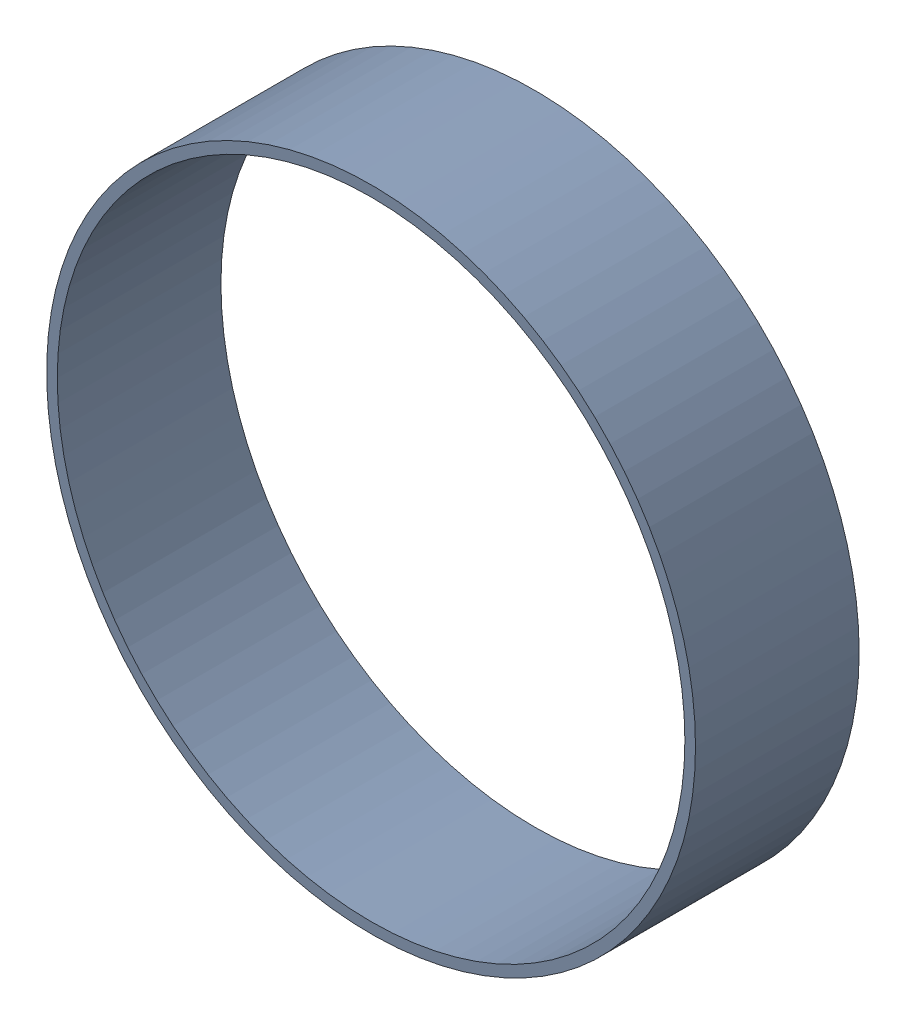
SolidWorks assembly Pad Free-4(5.842mm,1.016mm) on Multi-Layer, configuration Predeterminado. Lengths in mm.
Overall size (1.55 1.55 0.39).
2 component instances, 1 part files, 0 mates.
Components (placement in the parent):
- Pad Hole-2-1: Pad Hole-2 [Predeterminado] at (5.842 1.016 -0.4013) size (1.55 1.55 0.39)
  - Pad Hole-Part-1-2-1: Pad Hole-Part-1-2 [Predeterminado] at origin size (1.55 1.55 0.39)
